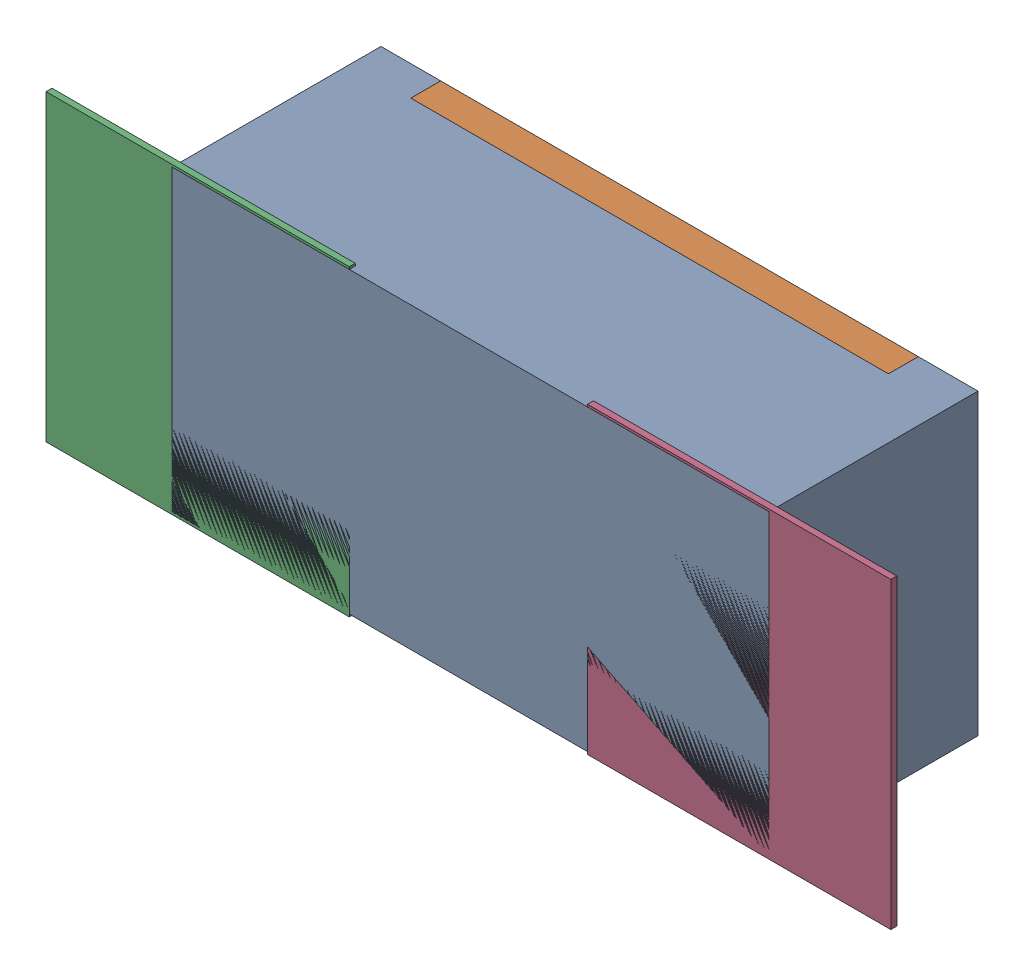
SolidWorks assembly R153, configuration Défaut. Lengths in mm.
Overall size (1.42 0.51 0.35).
5 component instances, 2 part files, 0 mates.
Components (placement in the parent):
- R0402-1: R0402 [Défaut] at (4.2418 -6.8707 -2.0818) x (1 0 0) z (0 0 -1) size (1 0.5 0.35)
- 6504207776-1: 6504207776 [Défaut] at (3.7847 -6.8708 -2.0918) size (0.51 0.51 0.01)
  - Extruded-1: Extruded [Défaut] at origin size (0.51 0.51 0.01)
- 6504207776-2: 6504207776 [Défaut] at (4.6918 -6.8708 -2.0918) size (0.51 0.51 0.01)
  - Extruded-1: Extruded [Défaut] at origin size (0.51 0.51 0.01)
